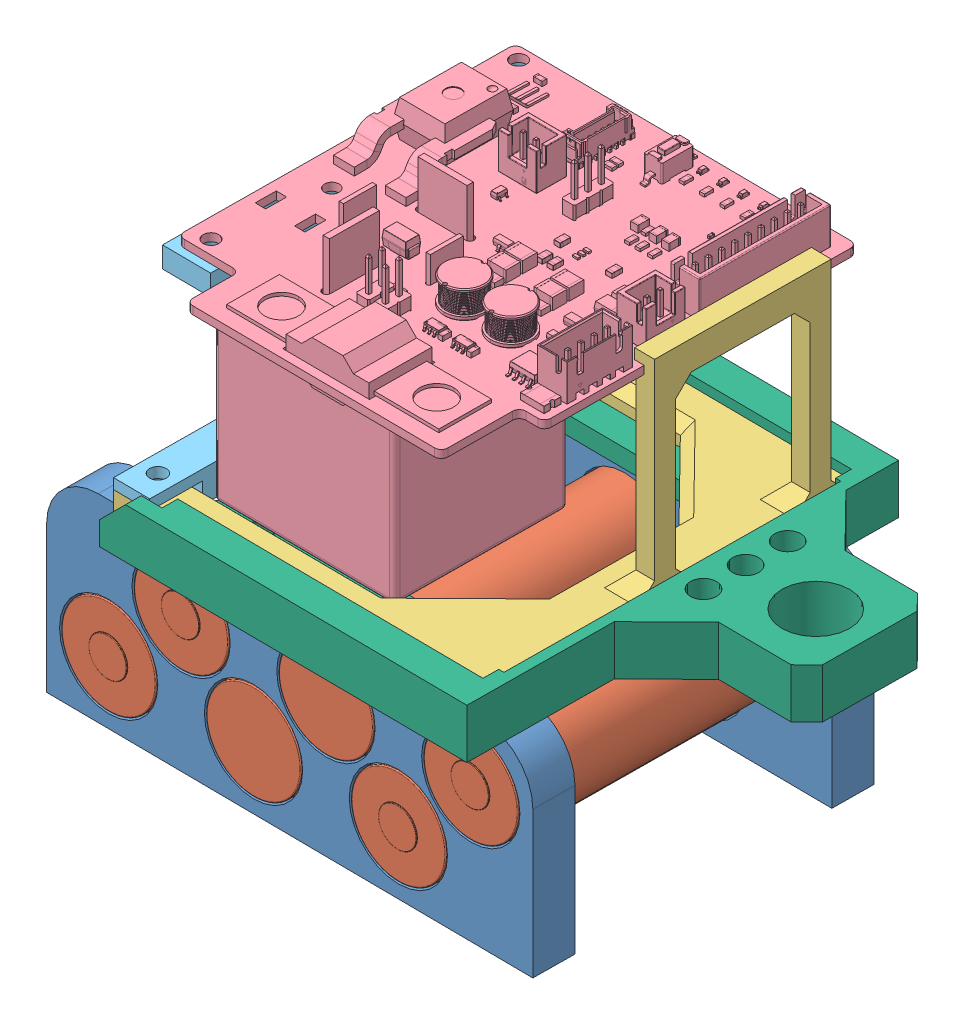
SolidWorks assembly testing_assembly, configuration Domyślna. Lengths in mm.
Overall size (117.64 92.27 82.85).
12 component instances, 6 part files, 27 mates.
Components (placement in the parent):
- testing_holder_for_batteries-1: testing_holder_for_batteries [Domyślna] at (-0.1661 0 66.4695) x (0.999962 0 0.008727) z (-0.008727 0 0.999962) size (94 38 8)
- US18650VTC6.stp-1: US18650VTC6.stp [Domyślna] at (-186.4849 13.9918 8.0413) x (0.999962 0 0.008727) z (-0.008727 0 0.999962) size (18.35 18.35 65)
- US18650VTC6.stp-2: US18650VTC6.stp [Domyślna] at (-172.4854 27.9918 8.1635) x (0.999962 0 0.008727) z (-0.008727 0 0.999962) size (18.35 18.35 65)
- US18650VTC6.stp-3: US18650VTC6.stp [Domyślna] at (-159.0514 13.9918 73.0832) x (-0.999962 0 -0.008727) z (0.008727 0 -0.999962) size (18.35 18.35 65)
- US18650VTC6.stp-4: US18650VTC6.stp [Domyślna] at (-145.052 27.9918 73.2054) x (-0.999962 0 -0.008727) z (0.008727 0 -0.999962) size (18.35 18.35 65)
- US18650VTC6.stp-5: US18650VTC6.stp [Domyślna] at (-116.4875 27.9918 8.6522) x (0.999962 0 0.008727) z (-0.008727 0 0.999962) size (18.35 18.35 65)
- US18650VTC6.stp-6: US18650VTC6.stp [Domyślna] at (-130.487 13.9918 8.53) x (0.999962 0 0.008727) z (-0.008727 0 0.999962) size (18.35 18.35 65)
- testing_holder_for_batteries-2: testing_holder_for_batteries [Domyślna] at (0.3296 0 9.6716) x (0.999962 0 0.008727) z (-0.008727 0 0.999962) size (94 38 8)
- testing_holder_bottom_side-1: testing_holder_bottom_side [Domyślna] at (-183.8482 -18.5636 81.7671) x (-0.008727 0 0.999962) z (0 -1 0) size (75.7 69.67 43.75)
- LV_BMS_PCB_V2.step-1: LV_BMS_PCB_V2.step [Domyślna] at (-178.4843 85.2455 3.4295) x (-0.008727 0 0.999962) z (0 1 0) size (74.3 66.04 50.52)
- testing_holder_front_side-1: testing_holder_front_side [Domyślna] at (-183.8482 47.4918 81.7671) x (0.008727 0 -0.999962) z (0 1 0) size (75.7 9.29 40)
- Part8^testing_assembly-1: Part8^testing_assembly [Domyślna] at (-3.0419 39.9918 11.5905) x (0.999962 0 0.008727) z (0 1 0) size (98 82 9.5) (virtual)
Mates (geometry in assembly coordinates):
- Concentric1: concentric aligned: cylinder of Part2^Assem1-1 through (-187.0504 13.9918 72.8388) axis (0.008727 0 -0.999962) radius 9.5; cylinder of US18650VTC6.stp-1 through (-187.0504 13.9918 72.8388) axis (0.008727 0 -0.999962) radius 9.175
- Concentric2: concentric aligned: cylinder of Part2^Assem1-1 through (-173.0509 27.9918 72.961) axis (0.008727 0 -0.999962) radius 9.5; cylinder of US18650VTC6.stp-2 through (-173.0509 27.9918 72.961) axis (0.008727 0 -0.999962) radius 9.175
- Concentric3: concentric anti-aligned: cylinder of Part2^Assem1-1 through (-159.0514 13.9918 73.0832) axis (0.008727 0 -0.999962) radius 9.5; cylinder of US18650VTC6.stp-3 through (-158.4859 13.9918 8.2857) axis (-0.008727 0 0.999962) radius 9.175
- Distance1: distance = 0 mm aligned: plane of US18650VTC6.stp-1 through (-187.0504 13.9918 72.8388) normal (-0.008727 0 0.999962); plane of US18650VTC6.stp-2 through (-173.0509 27.9918 72.961) normal (-0.008727 0 0.999962)
- Distance2: distance = 0 mm aligned: plane of US18650VTC6.stp-1 through (-187.0504 13.9918 72.8388) normal (-0.008727 0 0.999962); plane of US18650VTC6.stp-3 through (-159.0514 13.9918 73.0832) normal (-0.008727 0 0.999962)
- Concentric4: concentric aligned: cylinder of Part2^Assem1-1 through (-131.0525 13.9918 73.3275) axis (0.008727 0 -0.999962) radius 9.5; cylinder of US18650VTC6.stp-6 through (-131.0525 13.9918 73.3275) axis (0.008727 0 -0.999962) radius 9.175
- Concentric5: concentric aligned: cylinder of Part2^Assem1-1 through (-117.053 27.9918 73.4497) axis (0.008727 0 -0.999962) radius 9.5; cylinder of US18650VTC6.stp-5 through (-117.053 27.9918 73.4497) axis (0.008727 0 -0.999962) radius 9.175
- Concentric6: concentric anti-aligned: cylinder of battery_pack_holder_for_batteries-1 through (-145.052 27.9918 73.2054) axis (0.008727 0 -0.999962) radius 9.5; cylinder of US18650VTC6.stp-4 through (-144.4865 27.9918 8.4078) axis (-0.008727 0 0.999962) radius 9.175
- Distance3: distance = 0 mm aligned: plane of US18650VTC6.stp-1 through (-187.0504 13.9918 72.8388) normal (-0.008727 0 0.999962); plane of US18650VTC6.stp-4 through (-145.052 27.9918 73.2054) normal (-0.008727 0 0.999962)
- Coincident5: coincident aligned: plane of US18650VTC6.stp-4 through (-145.052 27.9918 73.2054) normal (-0.008727 0 0.999962); plane of US18650VTC6.stp-5 through (-117.053 27.9918 73.4497) normal (-0.008727 0 0.999962)
- Coincident6: coincident aligned: plane of US18650VTC6.stp-1 through (-187.0504 13.9918 72.8388) normal (-0.008727 0 0.999962); plane of US18650VTC6.stp-6 through (-131.0525 13.9918 73.3275) normal (-0.008727 0 0.999962)
- Concentric7: concentric aligned: cylinder of US18650VTC6.stp-2 through (-173.0509 27.9918 72.961) axis (0.008727 0 -0.999962) radius 9.175; cylinder of battery_pack_holder_for_batteries-2 through (-172.5552 27.9918 16.1632) axis (0.008727 0 -0.999962) radius 9.5
- Coincident9: coincident anti-aligned: plane of BMS_holder-1 through (-113.1308 -18.5636 82.3843) normal (-0.999962 0 -0.008727); plane of LV_BMS_PCB_V2.step-1 through (-112.9544 83.7418 62.1696) normal (0.999962 0 0.008727)
- Coincident10: coincident anti-aligned: plane of BMS_holder-1 through (-183.8482 85.2455 81.7671) normal (0 -1 0); plane of LV_BMS_PCB_V2.step-1 through (-145.6338 85.2455 39.9654) normal (0 1 0)
- Distance5: distance = 6.9 mm aligned: plane of BMS_holder-1 through (-114.3457 87.2455 10.8895) normal (0.008727 0 -0.999962); plane of LV_BMS_PCB_V2.step-1 through (-113.7168 83.7418 3.9947) normal (0.008727 0 -0.999962)
- Distance6: distance = 0 mm aligned: plane of BMS_HOLDER_screw_connector_for_pcb-1 through (-180.7983 47.4918 81.7937) normal (-0.999962 0 -0.008727); plane of BMS_holder-1 through (-180.7983 47.4918 81.7937) normal (-0.999962 0 -0.008727)
- Coincident17: coincident aligned: plane of BMS_holder-1 through (-112.2408 43.4918 2.989) normal (0 -1 0); plane of BMS_HOLDER_screw_connector_for_pcb-1 through (-173.7986 43.4918 81.8548) normal (0 -1 0)
- Coincident19: coincident aligned: plane of US18650VTC6.stp-6 through (-130.487 13.9918 8.53) normal (0.008727 0 -0.999962); plane of battery_pack_holder_for_batteries-2 through (0.3296 0 9.6716) normal (0.008727 0 -0.999962)
- Coincident22: coincident aligned: plane of battery_pack_holder_for_batteries-1 through (-0.2359 0 74.4691) normal (-0.008727 0 0.999962); plane of US18650VTC6.stp-2 through (-173.0509 27.9918 72.961) normal (-0.008727 0 0.999962)
- Distance9: distance = 1.9 mm aligned: plane of battery_pack_holder_for_batteries-2 through (0.2598 0 17.6713) normal (-0.008727 0 0.999962); plane of Part8^testing_battery_pack_assembly-1 through (-3.1113 43.4918 19.542) normal (-0.008727 0 0.999962)
- Coincident28: coincident anti-aligned: plane of battery_pack_holder_for_batteries-2 through (-198.5542 39.9918 15.9363) normal (0 1 0); plane of Part8^testing_battery_pack_assembly-1 through (-3.0419 39.9918 11.5905) normal (0 -1 0)
- Coincident29: coincident aligned: plane of BMS_holder-1 through (-183.1562 47.4918 2.4701) normal (0.008727 0 -0.999962); plane of BMS_HOLDER_screw_connector_for_pcb-1 through (-173.1066 47.4918 2.5578) normal (0.008727 0 -0.999962)
- Parallel3: parallel aligned: plane of BMS_holder-1 through (-180.7983 47.4918 81.7937) normal (-0.999962 0 -0.008727); plane of BMS_HOLDER_screw_connector_for_pcb-1 through (-180.7983 47.4918 81.7937) normal (-0.999962 0 -0.008727)
- Distance10: distance = 4 mm aligned: plane of battery_pack_holder_for_batteries-2 through (-104.5578 39.9918 16.7566) normal (0.999962 0 0.008727); plane of Part8^testing_battery_pack_assembly-1 through (-108.5048 43.4918 10.6701) normal (0.999962 0 0.008727)
- Coincident34: coincident anti-aligned: plane of BMS_holder-1 through (-111.1309 -18.5636 82.4017) normal (0.999962 0 0.008727); plane of Part8^testing_battery_pack_assembly-1 through (-110.5048 49.4918 10.6527) normal (-0.999962 0 -0.008727)
- Coincident35: coincident anti-aligned: plane of BMS_holder-1 through (-183.1562 47.4918 2.4701) normal (0.008727 0 -0.999962); plane of Part8^testing_battery_pack_assembly-1 through (-2.976 49.4918 4.0426) normal (-0.008727 0 0.999962)
- Coincident36: coincident anti-aligned: plane of BMS_holder-1 through (-112.2408 43.4918 2.989) normal (0 -1 0); plane of Part8^testing_battery_pack_assembly-1 through (-3.0419 43.4918 11.5905) normal (0 1 0)
